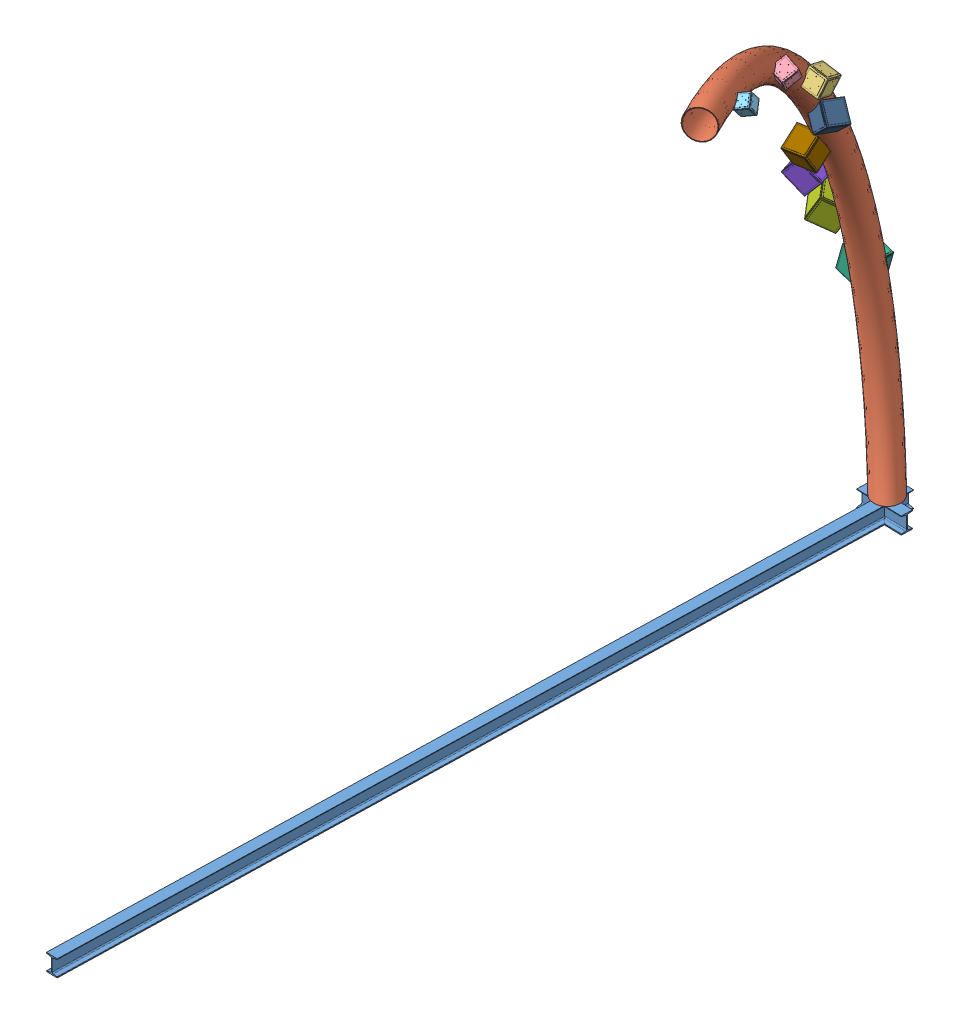
SolidWorks assembly tube4A - with dimensions, configuration Default. Lengths in mm.
Overall size (1783.34 3986.95 5743.22).
11 component instances, 11 part files, 27 mates.
Components (placement in the parent):
- cube_positions-1: cube_positions [Default] at (8904.7669 0 -1666.8962) x (-0.98414 0 0.177396) z (-0.177396 0 -0.98414) size (10173.18 3894.08 5705.72) (hidden)
- ground_anchor^tube4A - with dimensions-1: ground_anchor^tube4A - with dimensions [Default] at (9566.8333 -60.325 -1104.0246) x (-0.999452 0 0.033088) z (0 -1 0) size (470.34 5095.97 101.6) (virtual)
- tubes-1: tubes [tube4A] at (840.8937 1535.1212 -511.9514) x (0.194163 0.849473 0.490608) z (0.490608 -0.517175 0.701309) size (3976.83 178.46 1081.85)
- cube_06-2: cube_06 [Default] at (471.5315 2748.7735 -1138.0748) x (0.201369 0.905147 -0.374379) z (0.964745 -0.249399 -0.084066) size (112.39 112.39 116.4)
- cube_07-2: cube_07 [Default] at (645.566 3070.0096 -753.4371) x (0.234737 0.447214 -0.863075) z (0.927023 -0.370117 0.060349) size (97.16 97.16 101.09)
- cube_08-2: cube_08 [Default] at (942.6163 3319.9065 -214.0269) x (-0.520827 0.525094 -0.673064) z (0.853659 0.322603 -0.408894) size (81.92 81.92 85.85)
- cube_01-2: cube_01 [Default] at (-37.904 1151.3192 -1919.5434) x (-0.033713 0.00175 0.99943) z (-0.959686 0.279148 -0.032861) size (163.19 163.19 163.19)
- cube_02-2: cube_02 [Default] at (-88.0911 1506.3364 -1758.7081) x (0.627621 -0.148413 0.764242) z (-0.63488 0.470576 0.612769) size (158.12 158.12 158.12)
- cube_03-2: cube_03 [Default] at (-39.521 1804.2306 -1588.2847) x (0.643801 0.761931 -0.070581) z (-0.729232 0.638874 0.245073) size (150.61 150.49 150.49)
- cube_04-2: cube_04 [Default] at (125.08 2085.0042 -1403.7965) x (0.992472 0.073499 -0.097969) z (-0.011929 0.85412 0.519939) size (140.33 142.17 140.33)
- cube_05-2: cube_05 [Default] at (346.6784 2408.9309 -1315.8693) x (0.718959 0.693701 0.043313) z (-0.249968 0.199916 0.947391) size (127.64 128.2 127.64)
Mates (geometry in assembly coordinates):
- Lock1: lock: unknown of assembly; unknown of ?
- Coincident1: coincident anti-aligned: plane of ground_anchor^tube4A - with dimensions-1 through (449.1246 0 3216.5534) normal (0 -1 0); plane of assembly through (0 0 0) normal (0 1 0)
- Coincident2: coincident aligned: plane of cube_positions-1 through (290.8601 2818.3314 -1040.6765) normal (-0.964745 0.249399 0.084066); plane of ? through (273.0562 2780.0027 -1131.2857) normal (-0.964745 0.249399 0.084066)
- Coincident3: coincident aligned: plane of cube_positions-1 through (391.4267 2792.3336 -1049.4396) normal (0.169461 0.344252 0.923457); plane of ? through (302.0514 2811.2686 -1040.0973) normal (0.169461 0.344252 0.923457)
- Coincident4: coincident aligned: plane of cube_positions-1 through (352.7707 2662.0943 -1106.6765) normal (-0.201369 -0.905147 0.374379); plane of ? through (279.8176 2716.5511 -1014.2543) normal (-0.201369 -0.905147 0.374379)
- Coincident5: coincident aligned: plane of cube_positions-1 through (529.5721 2928.2446 -651.0495) normal (-0.234737 -0.447214 0.863075); plane of ? through (472.6851 3024.1588 -616.8223) normal (-0.234737 -0.447214 0.863075)
- Coincident6: coincident aligned: plane of cube_positions-1 through (555.7789 3001.2111 -606.1133) normal (0.29245 0.814257 0.501457); plane of ? through (496.1249 3071.64 -685.6843) normal (0.29245 0.814257 0.501457)
- Coincident7: coincident aligned: plane of cube_positions-1 through (529.5721 2928.2446 -651.0495) normal (0.927023 -0.370117 0.060349); plane of ? through (572.7933 3030.8022 -685.9928) normal (0.927023 -0.370117 0.060349)
- Coincident8: coincident aligned: plane of cube_positions-1 through (958.6365 3187.3449 -144.6636) normal (0.520827 -0.525094 0.673064); plane of ? through (896.5032 3255.773 -43.1995) normal (0.520827 -0.525094 0.673064)
- Coincident9: coincident aligned: plane of cube_positions-1 through (958.6365 3187.3449 -144.6636) normal (0.853659 0.322603 -0.408894); plane of ? through (920.9236 3217.9385 -199.2603) normal (0.853659 0.322603 -0.408894)
- Coincident10: coincident aligned: plane of cube_positions-1 through (894.6285 3163.1558 -114.0044) normal (-0.002425 0.78753 0.616271); plane of ? through (859.0501 3202.016 -163.8037) normal (-0.002425 0.78753 0.616271)
- Coincident11: coincident aligned: plane of cube_positions-1 through (327.9374 1299.244 -1832.7332) normal (-0.009503 -0.287348 -0.957779); plane of cube_01-2
- Coincident12: coincident aligned: plane of cube_positions-1 through (327.9374 1299.244 -1832.7332) normal (-0.002851 0.957826 -0.287334); plane of cube_01-2
- Coincident13: coincident aligned: plane of cube_positions-1 through (329.3857 1343.0359 -1686.7676) normal (0.999951 0 -0.009921); plane of cube_01-2
- Coincident14: coincident aligned: plane of cube_positions-1 through (223.4586 1552.0894 -1822.9385) normal (0.48311 -0.393919 -0.781942); plane of cube_02-2
- Coincident15: coincident aligned: plane of cube_positions-1 through (254.2553 1688.8052 -1872.7847) normal (0.207047 0.919145 -0.335118); plane of cube_02-2
- Coincident16: coincident aligned: plane of cube_positions-1 through (349.9978 1552.0894 -1744.7584) normal (0.850727 0 0.525608); plane of cube_02-2
- Coincident17: coincident: plane of cube_positions-1 through (330.0926 1977.2247 -1810.7438) normal (0.835276 -0.271588 -0.478074); plane of cube_03-2
- Coincident18: coincident: plane of cube_positions-1 through (330.0926 1977.2247 -1810.7438) normal (-0.184579 0.680529 -0.709091); plane of cube_03-2
- Coincident19: coincident aligned: plane of cube_positions-1 through (212.2165 2015.5519 -1743.2769) normal (0.517924 0.680529 0.5183); plane of cube_03-2
- Coincident20: coincident: plane of cube_positions-1 through (314.0427 2114.7494 -1584.7954) normal (0.090394 -0.23703 -0.967288); plane of cube_04-2
- Coincident21: coincident: plane of cube_positions-1 through (280.6852 2237.0994 -1617.8941) normal (-0.254513 0.933513 -0.252538); plane of cube_04-2
- Coincident22: coincident aligned: plane of cube_positions-1 through (314.0427 2114.7494 -1584.7954) normal (0.962835 0.269016 0.024057); plane of cube_04-2
- Coincident23: coincident: plane of cube_positions-1 through (232.3027 2359.0281 -1336.4217) normal (0.106497 -0.478574 -0.871565); line of cube_05-2 through (313.6743 2401.8885 -1350.0134) axis (0.046336 -0.873209 0.485139)
- Coincident24: coincident: plane of cube_positions-1 through (298.8916 2496.3444 -1267.9955) normal (-0.735086 0.552362 -0.393121); plane of cube_05-2
- Coincident25: coincident aligned: plane of cube_positions-1 through (385.8246 2431.0207 -1221.5041) normal (0.669557 0.682541 -0.292969); unknown of ?
- Sketch2: unknown = 254 mm: unknown of cube_05-2; unknown of cube_05-2; unknown of cube_05-2; unknown of cube_04-2; unknown of cube_04-2; unknown of cube_03-2; unknown of cube_03-2; unknown of cube_03-2; unknown of cube_02-2; unknown of cube_02-2; unknown of cube_02-2; unknown of cube_01-2; unknown of cube_01-2; unknown of tubes-1; unknown of cube_04-2; unknown of tubes-1
